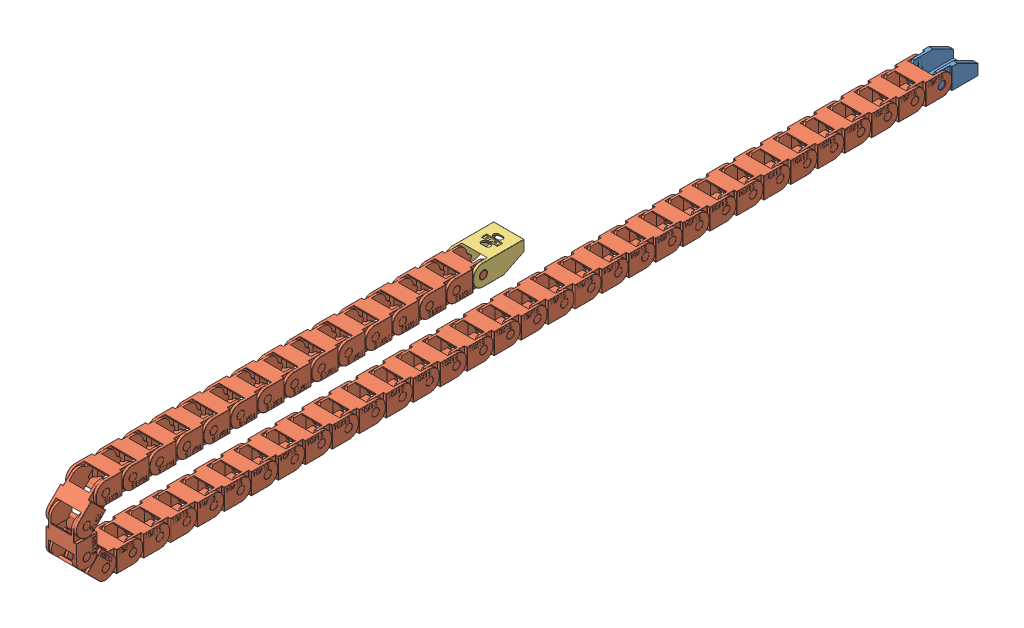
SolidWorks assembly Drag Chain Unit, configuration Default. Lengths in mm.
Overall size (23 71.62 674.15).
50 component instances, 3 part files, 147 mates.
Components (placement in the parent):
- Drag Chain 10x15 M-End-1: Drag Chain 10x15 M-End [Default] at origin size (21.7 15.5 37.5)
- Drag Chain 10x15 Inner-1: Drag Chain 10x15 Inner [Default] x (-1 0 0) z (0 0 1) size (23 15.5 37.5)
- Drag Chain 10x15 Inner-2: Drag Chain 10x15 Inner [Default] at (0 0 20) x (-1 0 0) z (0 0 1) size (23 15.5 37.5)
- Drag Chain 10x15 Inner-3: Drag Chain 10x15 Inner [Default] at (0 0 40) x (-1 0 0) z (0 0 1) size (23 15.5 37.5)
- Drag Chain 10x15 Inner-4: Drag Chain 10x15 Inner [Default] at (0 0 60) x (-1 0 0) z (0 0 1) size (23 15.5 37.5)
- Drag Chain 10x15 Inner-5: Drag Chain 10x15 Inner [Default] at (0 0 80) x (-1 0 0) z (0 0 1) size (23 15.5 37.5)
- Drag Chain 10x15 Inner-6: Drag Chain 10x15 Inner [Default] at (0 0 100) x (-1 0 0) z (0 0 1) size (23 15.5 37.5)
- Drag Chain 10x15 Inner-7: Drag Chain 10x15 Inner [Default] at (0 0 120) x (-1 0 0) z (0 0 1) size (23 15.5 37.5)
- Drag Chain 10x15 Inner-8: Drag Chain 10x15 Inner [Default] at (0 0 140) x (-1 0 0) z (0 0 1) size (23 15.5 37.5)
- Drag Chain 10x15 Inner-9: Drag Chain 10x15 Inner [Default] at (0 0 160) x (-1 0 0) z (0 0 1) size (23 15.5 37.5)
- Drag Chain 10x15 Inner-10: Drag Chain 10x15 Inner [Default] at (0 0 180) x (-1 0 0) z (0 0 1) size (23 15.5 37.5)
- Drag Chain 10x15 Inner-11: Drag Chain 10x15 Inner [Default] at (0 0 200) x (-1 0 0) z (0 0 1) size (23 15.5 37.5)
- Drag Chain 10x15 Inner-12: Drag Chain 10x15 Inner [Default] at (0 0 220) x (-1 0 0) z (0 0 1) size (23 15.5 37.5)
- Drag Chain 10x15 Inner-13: Drag Chain 10x15 Inner [Default] at (0 0 240) x (-1 0 0) z (0 0 1) size (23 15.5 37.5)
- Drag Chain 10x15 Inner-14: Drag Chain 10x15 Inner [Default] at (0 0 260) x (-1 0 0) z (0 0 1) size (23 15.5 37.5)
- Drag Chain 10x15 Inner-15: Drag Chain 10x15 Inner [Default] at (0 0 280) x (-1 0 0) z (0 0 1) size (23 15.5 37.5)
- Drag Chain 10x15 Inner-16: Drag Chain 10x15 Inner [Default] at (0 0 300) x (-1 0 0) z (0 0 1) size (23 15.5 37.5)
- Drag Chain 10x15 Inner-17: Drag Chain 10x15 Inner [Default] at (0 0 320) x (-1 0 0) z (0 0 1) size (23 15.5 37.5)
- Drag Chain 10x15 Inner-18: Drag Chain 10x15 Inner [Default] at (0 0 340) x (-1 0 0) z (0 0 1) size (23 15.5 37.5)
- Drag Chain 10x15 Inner-19: Drag Chain 10x15 Inner [Default] at (0 0 360) x (-1 0 0) z (0 0 1) size (23 15.5 37.5)
- Drag Chain 10x15 Inner-20: Drag Chain 10x15 Inner [Default] at (0 0 380) x (-1 0 0) z (0 0 1) size (23 15.5 37.5)
- Drag Chain 10x15 Inner-21: Drag Chain 10x15 Inner [Default] at (0 0 400) x (-1 0 0) z (0 0 1) size (23 15.5 37.5)
- Drag Chain 10x15 Inner-22: Drag Chain 10x15 Inner [Default] at (0 0 420) x (-1 0 0) z (0 0 1) size (23 15.5 37.5)
- Drag Chain 10x15 Inner-23: Drag Chain 10x15 Inner [Default] at (0 0 440) x (-1 0 0) z (0 0 1) size (23 15.5 37.5)
- Drag Chain 10x15 Inner-24: Drag Chain 10x15 Inner [Default] at (0 0 460) x (-1 0 0) z (0 0 1) size (23 15.5 37.5)
- Drag Chain 10x15 Inner-25: Drag Chain 10x15 Inner [Default] at (0 0 480) x (-1 0 0) z (0 0 1) size (23 15.5 37.5)
- Drag Chain 10x15 Inner-26: Drag Chain 10x15 Inner [Default] at (0 0 500) x (-1 0 0) z (0 0 1) size (23 15.5 37.5)
- Drag Chain 10x15 Inner-27: Drag Chain 10x15 Inner [Default] at (0 0 520) x (-1 0 0) z (0 0 1) size (23 15.5 37.5)
- Drag Chain 10x15 Inner-28: Drag Chain 10x15 Inner [Default] at (0 0 540) x (-1 0 0) z (0 0 1) size (23 15.5 37.5)
- Drag Chain 10x15 Inner-29: Drag Chain 10x15 Inner [Default] at (0 0 560) x (-1 0 0) z (0 0 1) size (23 15.5 37.5)
- Drag Chain 10x15 Inner-30: Drag Chain 10x15 Inner [Default] at (0 0 580) x (-1 0 0) z (0 0 1) size (23 15.5 37.5)
- Drag Chain 10x15 Inner-31: Drag Chain 10x15 Inner [Default] at (0 0 600) x (-1 0 0) z (0 0 1) size (23 15.5 37.5)
- Drag Chain 10x15 Inner-32: Drag Chain 10x15 Inner [Default] at (0 0 620) x (-1 0 0) z (0 0.707107 0.707107) size (23 15.5 37.5)
- Drag Chain 10x15 Inner-33: Drag Chain 10x15 Inner [Default] at (0 14.1421 634.1421) x (-1 0 0) z (0 1 0) size (23 15.5 37.5)
- Drag Chain 10x15 Inner-34: Drag Chain 10x15 Inner [Default] at (0 34.1421 634.1421) x (-1 0 0) z (0 0.707107 -0.707107) size (23 15.5 37.5)
- Drag Chain 10x15 Inner-35: Drag Chain 10x15 Inner [Default] at (0 48.2843 620) x (-1 0 0) z (0 0 -1) size (23 15.5 37.5)
- Drag Chain 10x15 Inner-36: Drag Chain 10x15 Inner [Default] at (0 48.2843 600) x (-1 0 0) z (0 0 -1) size (23 15.5 37.5)
- Drag Chain 10x15 Inner-37: Drag Chain 10x15 Inner [Default] at (0 48.2843 580) x (-1 0 0) z (0 0 -1) size (23 15.5 37.5)
- Drag Chain 10x15 Inner-38: Drag Chain 10x15 Inner [Default] at (0 48.2843 560) x (-1 0 0) z (0 0 -1) size (23 15.5 37.5)
- Drag Chain 10x15 Inner-39: Drag Chain 10x15 Inner [Default] at (0 48.2843 540) x (-1 0 0) z (0 0 -1) size (23 15.5 37.5)
- Drag Chain 10x15 Inner-40: Drag Chain 10x15 Inner [Default] at (0 48.2843 520) x (-1 0 0) z (0 0 -1) size (23 15.5 37.5)
- Drag Chain 10x15 Inner-41: Drag Chain 10x15 Inner [Default] at (0 48.2843 500) x (-1 0 0) z (0 0 -1) size (23 15.5 37.5)
- Drag Chain 10x15 Inner-42: Drag Chain 10x15 Inner [Default] at (0 48.2843 480) x (-1 0 0) z (0 0 -1) size (23 15.5 37.5)
- Drag Chain 10x15 Inner-43: Drag Chain 10x15 Inner [Default] at (0 48.2843 460) x (-1 0 0) z (0 0 -1) size (23 15.5 37.5)
- Drag Chain 10x15 Inner-44: Drag Chain 10x15 Inner [Default] at (0 48.2843 440) x (-1 0 0) z (0 0 -1) size (23 15.5 37.5)
- Drag Chain 10x15 Inner-45: Drag Chain 10x15 Inner [Default] at (0 48.2843 420) x (-1 0 0) z (0 0 -1) size (23 15.5 37.5)
- Drag Chain 10x15 Inner-46: Drag Chain 10x15 Inner [Default] at (0 48.2843 400) x (-1 0 0) z (0 0 -1) size (23 15.5 37.5)
- Drag Chain 10x15 Inner-47: Drag Chain 10x15 Inner [Default] at (0 48.2843 380) x (-1 0 0) z (0 0 -1) size (23 15.5 37.5)
- Drag Chain 10x15 Inner-48: Drag Chain 10x15 Inner [Default] at (0 48.2843 360) x (-1 0 0) z (0 0 -1) size (23 15.5 37.5)
- Drag Chain 10x15 F-End-1: Drag Chain 10x15 F-End [Default] at (0 48.2843 340) x (1 0 0) z (0 0 -1) size (22.5 15.5 37.5)
Mates (geometry in assembly coordinates):
- Coincident1: coincident: plane of assembly; plane of assembly; plane of Drag Chain 10x15 M-End-1 through (9.4 7.25 1.3258) normal (1 0 0); plane of Drag Chain 10x15 Inner-1 through (9.4 7.75 -7.35) normal (-1 0 0)
- Concentric1: concentric: cylinder of assembly; cylinder of assembly; cylinder of Drag Chain 10x15 M-End-1 through (9.4 0 0) axis (1 0 0) radius 2.8; cylinder of Drag Chain 10x15 Inner-1 through (-11.35 0 0) axis (1 0 0) radius 2.85
- Coincident2: coincident: plane of assembly; plane of assembly; plane of Drag Chain 10x15 M-End-1 through (10.85 -7.75 10.65) normal (0 -1 0); plane of Drag Chain 10x15 Inner-1 through (-11.35 -7.75 -7.35) normal (0 -1 0)
- Coincident3: coincident: plane of assembly; plane of assembly; plane of Drag Chain 10x15 Inner-1 through (9.4 -7.25 20.5989) normal (1 0 0); plane of Drag Chain 10x15 Inner-2 through (9.4 7.75 12.65) normal (-1 0 0)
- Concentric2: concentric: cylinder of assembly; cylinder of assembly; cylinder of Drag Chain 10x15 Inner-1 through (9.4 0 20) axis (1 0 0) radius 2.8; cylinder of Drag Chain 10x15 Inner-2 through (-11.35 0 20) axis (1 0 0) radius 2.85
- Coincident4: coincident: plane of assembly; plane of assembly; plane of Drag Chain 10x15 Inner-1 through (-11.35 -7.75 -7.35) normal (0 -1 0); plane of Drag Chain 10x15 Inner-2 through (-11.35 -7.75 12.65) normal (0 -1 0)
- Coincident5: coincident: plane of assembly; plane of assembly; plane of Drag Chain 10x15 Inner-2 through (9.4 -7.25 40.5989) normal (1 0 0); plane of Drag Chain 10x15 Inner-3 through (9.4 7.75 32.65) normal (-1 0 0)
- Concentric3: concentric: cylinder of assembly; cylinder of assembly; cylinder of Drag Chain 10x15 Inner-2 through (9.4 0 40) axis (1 0 0) radius 2.8; cylinder of Drag Chain 10x15 Inner-3 through (-11.35 0 40) axis (1 0 0) radius 2.85
- Coincident7: coincident: plane of assembly; plane of assembly; plane of Drag Chain 10x15 Inner-2 through (-11.35 -7.75 12.65) normal (0 -1 0); plane of Drag Chain 10x15 Inner-3 through (-11.35 -7.75 32.65) normal (0 -1 0)
- Coincident8: coincident: plane of assembly; plane of assembly; plane of Drag Chain 10x15 Inner-3 through (9.4 -7.25 60.5989) normal (1 0 0); plane of Drag Chain 10x15 Inner-4 through (9.4 7.75 52.65) normal (-1 0 0)
- Concentric4: concentric: cylinder of assembly; cylinder of assembly; cylinder of Drag Chain 10x15 Inner-3 through (9.4 0 60) axis (1 0 0) radius 2.8; cylinder of Drag Chain 10x15 Inner-4 through (-11.35 0 60) axis (1 0 0) radius 2.85
- Coincident9: coincident: plane of assembly; plane of assembly; plane of Drag Chain 10x15 Inner-3 through (-11.35 -7.75 32.65) normal (0 -1 0); plane of Drag Chain 10x15 Inner-4 through (-11.35 -7.75 52.65) normal (0 -1 0)
- Coincident10: coincident: plane of assembly; plane of assembly; plane of Drag Chain 10x15 Inner-4 through (9.4 -7.25 80.5989) normal (1 0 0); plane of Drag Chain 10x15 Inner-5 through (9.4 7.75 72.65) normal (-1 0 0)
- Concentric5: concentric: cylinder of assembly; cylinder of assembly; cylinder of Drag Chain 10x15 Inner-4 through (9.4 0 80) axis (1 0 0) radius 2.8; cylinder of Drag Chain 10x15 Inner-5 through (-11.35 0 80) axis (1 0 0) radius 2.85
- Coincident11: coincident: plane of assembly; plane of assembly; plane of Drag Chain 10x15 Inner-4 through (-11.35 -7.75 52.65) normal (0 -1 0); plane of Drag Chain 10x15 Inner-5 through (-11.35 -7.75 72.65) normal (0 -1 0)
- Coincident12: coincident: plane of assembly; plane of assembly; plane of Drag Chain 10x15 Inner-5 through (9.4 -7.25 100.5989) normal (1 0 0); plane of Drag Chain 10x15 Inner-6 through (9.4 7.75 92.65) normal (-1 0 0)
- Concentric6: concentric: cylinder of assembly; cylinder of assembly; cylinder of Drag Chain 10x15 Inner-5 through (9.4 0 100) axis (1 0 0) radius 2.8; cylinder of Drag Chain 10x15 Inner-6 through (-11.35 0 100) axis (1 0 0) radius 2.85
- Coincident13: coincident: plane of assembly; plane of assembly; plane of Drag Chain 10x15 Inner-5 through (-11.35 -7.75 72.65) normal (0 -1 0); plane of Drag Chain 10x15 Inner-6 through (-11.35 -7.75 92.65) normal (0 -1 0)
- Coincident14: coincident: plane of assembly; plane of assembly; plane of Drag Chain 10x15 Inner-6 through (9.4 -7.25 120.5989) normal (1 0 0); plane of Drag Chain 10x15 Inner-7 through (9.4 7.75 112.65) normal (-1 0 0)
- Concentric7: concentric: cylinder of assembly; cylinder of assembly; cylinder of Drag Chain 10x15 Inner-6 through (9.4 0 120) axis (1 0 0) radius 2.8; cylinder of Drag Chain 10x15 Inner-7 through (-11.35 0 120) axis (1 0 0) radius 2.85
- Coincident15: coincident: plane of assembly; plane of assembly; plane of Drag Chain 10x15 Inner-6 through (-11.35 -7.75 92.65) normal (0 -1 0); plane of Drag Chain 10x15 Inner-7 through (-11.35 -7.75 112.65) normal (0 -1 0)
- Coincident16: coincident: plane of assembly; plane of assembly; plane of Drag Chain 10x15 Inner-7 through (9.4 -7.25 140.5989) normal (1 0 0); plane of Drag Chain 10x15 Inner-8 through (9.4 7.75 132.65) normal (-1 0 0)
- Concentric8: concentric: cylinder of assembly; cylinder of assembly; cylinder of Drag Chain 10x15 Inner-7 through (9.4 0 140) axis (1 0 0) radius 2.8; cylinder of Drag Chain 10x15 Inner-8 through (-11.35 0 140) axis (1 0 0) radius 2.85
- Coincident17: coincident: plane of assembly; plane of assembly; plane of Drag Chain 10x15 Inner-7 through (-11.35 -7.75 112.65) normal (0 -1 0); plane of Drag Chain 10x15 Inner-8 through (-11.35 -7.75 132.65) normal (0 -1 0)
- Coincident18: coincident: plane of assembly; plane of assembly; plane of Drag Chain 10x15 Inner-8 through (9.4 -7.25 160.5989) normal (1 0 0); plane of Drag Chain 10x15 Inner-9 through (9.4 7.75 152.65) normal (-1 0 0)
- Concentric9: concentric: cylinder of assembly; cylinder of assembly; cylinder of Drag Chain 10x15 Inner-8 through (9.4 0 160) axis (1 0 0) radius 2.8; cylinder of Drag Chain 10x15 Inner-9 through (-11.35 0 160) axis (1 0 0) radius 2.85
- Coincident19: coincident: plane of assembly; plane of assembly; plane of Drag Chain 10x15 Inner-8 through (-11.35 -7.75 132.65) normal (0 -1 0); plane of Drag Chain 10x15 Inner-9 through (-11.35 -7.75 152.65) normal (0 -1 0)
- Coincident20: coincident: plane of assembly; plane of assembly; plane of Drag Chain 10x15 Inner-9 through (9.4 -7.25 180.5989) normal (1 0 0); plane of Drag Chain 10x15 Inner-10 through (9.4 7.75 172.65) normal (-1 0 0)
- Concentric10: concentric: cylinder of assembly; cylinder of assembly; cylinder of Drag Chain 10x15 Inner-9 through (9.4 0 180) axis (1 0 0) radius 2.8; cylinder of Drag Chain 10x15 Inner-10 through (-11.35 0 180) axis (1 0 0) radius 2.85
- Coincident21: coincident: plane of assembly; plane of assembly; plane of Drag Chain 10x15 Inner-9 through (-11.35 -7.75 152.65) normal (0 -1 0); plane of Drag Chain 10x15 Inner-10 through (-11.35 -7.75 172.65) normal (0 -1 0)
- Coincident22: coincident: plane of assembly; plane of assembly; plane of Drag Chain 10x15 Inner-10 through (9.4 -7.25 200.5989) normal (1 0 0); plane of Drag Chain 10x15 Inner-11 through (9.4 7.75 192.65) normal (-1 0 0)
- Concentric11: concentric: cylinder of assembly; cylinder of assembly; cylinder of Drag Chain 10x15 Inner-10 through (9.4 0 200) axis (1 0 0) radius 2.8; cylinder of Drag Chain 10x15 Inner-11 through (-11.35 0 200) axis (1 0 0) radius 2.85
- Coincident23: coincident: plane of assembly; plane of assembly; plane of Drag Chain 10x15 Inner-10 through (-11.35 -7.75 172.65) normal (0 -1 0); plane of Drag Chain 10x15 Inner-11 through (-11.35 -7.75 192.65) normal (0 -1 0)
- Coincident24: coincident: plane of assembly; plane of assembly; plane of Drag Chain 10x15 Inner-11 through (9.4 -7.25 220.5989) normal (1 0 0); plane of Drag Chain 10x15 Inner-12 through (9.4 7.75 212.65) normal (-1 0 0)
- Concentric12: concentric: cylinder of assembly; cylinder of assembly; cylinder of Drag Chain 10x15 Inner-11 through (9.4 0 220) axis (1 0 0) radius 2.8; cylinder of Drag Chain 10x15 Inner-12 through (-11.35 0 220) axis (1 0 0) radius 2.85
- Coincident25: coincident: plane of assembly; plane of assembly; plane of Drag Chain 10x15 Inner-11 through (-11.35 -7.75 192.65) normal (0 -1 0); plane of Drag Chain 10x15 Inner-12 through (-11.35 -7.75 212.65) normal (0 -1 0)
- Coincident26: coincident: plane of assembly; plane of assembly; plane of Drag Chain 10x15 Inner-12 through (9.4 -7.25 240.5989) normal (1 0 0); plane of Drag Chain 10x15 Inner-13 through (9.4 7.75 232.65) normal (-1 0 0)
- Concentric13: concentric: cylinder of assembly; cylinder of assembly; cylinder of Drag Chain 10x15 Inner-12 through (9.4 0 240) axis (1 0 0) radius 2.8; cylinder of Drag Chain 10x15 Inner-13 through (-11.35 0 240) axis (1 0 0) radius 2.85
- Coincident27: coincident: plane of assembly; plane of assembly; plane of Drag Chain 10x15 Inner-12 through (-11.35 -7.75 212.65) normal (0 -1 0); plane of Drag Chain 10x15 Inner-13 through (-11.35 -7.75 232.65) normal (0 -1 0)
- Coincident28: coincident: plane of assembly; plane of assembly; plane of Drag Chain 10x15 Inner-13 through (9.4 -7.25 260.5989) normal (1 0 0); plane of Drag Chain 10x15 Inner-14 through (9.4 7.75 252.65) normal (-1 0 0)
- Concentric14: concentric: cylinder of assembly; cylinder of assembly; cylinder of Drag Chain 10x15 Inner-13 through (9.4 0 260) axis (1 0 0) radius 2.8; cylinder of Drag Chain 10x15 Inner-14 through (-11.35 0 260) axis (1 0 0) radius 2.85
- Coincident29: coincident: plane of assembly; plane of assembly; plane of Drag Chain 10x15 Inner-13 through (-11.35 -7.75 232.65) normal (0 -1 0); plane of Drag Chain 10x15 Inner-14 through (-11.35 -7.75 252.65) normal (0 -1 0)
- Coincident30: coincident: plane of assembly; plane of assembly; plane of Drag Chain 10x15 Inner-14 through (9.4 -7.25 280.5989) normal (1 0 0); plane of Drag Chain 10x15 Inner-15 through (9.4 7.75 272.65) normal (-1 0 0)
- Concentric15: concentric: cylinder of assembly; cylinder of assembly; cylinder of Drag Chain 10x15 Inner-14 through (9.4 0 280) axis (1 0 0) radius 2.8; cylinder of Drag Chain 10x15 Inner-15 through (-11.35 0 280) axis (1 0 0) radius 2.85
- Coincident31: coincident: plane of assembly; plane of assembly; plane of Drag Chain 10x15 Inner-14 through (-11.35 -7.75 252.65) normal (0 -1 0); plane of Drag Chain 10x15 Inner-15 through (-11.35 -7.75 272.65) normal (0 -1 0)
- Coincident32: coincident: plane of assembly; plane of assembly; plane of Drag Chain 10x15 Inner-15 through (9.4 -7.25 300.5989) normal (1 0 0); plane of Drag Chain 10x15 Inner-16 through (9.4 7.75 292.65) normal (-1 0 0)
- Concentric16: concentric: cylinder of assembly; cylinder of assembly; cylinder of Drag Chain 10x15 Inner-15 through (9.4 0 300) axis (1 0 0) radius 2.8; cylinder of Drag Chain 10x15 Inner-16 through (-11.35 0 300) axis (1 0 0) radius 2.85
- Coincident33: coincident: plane of assembly; plane of assembly; plane of Drag Chain 10x15 Inner-15 through (-11.35 -7.75 272.65) normal (0 -1 0); plane of Drag Chain 10x15 Inner-16 through (-11.35 -7.75 292.65) normal (0 -1 0)
- Coincident34: coincident: plane of assembly; plane of assembly; plane of Drag Chain 10x15 Inner-16 through (9.4 -7.25 320.5989) normal (1 0 0); plane of Drag Chain 10x15 Inner-17 through (9.4 7.75 312.65) normal (-1 0 0)
- Concentric17: concentric: cylinder of assembly; cylinder of assembly; cylinder of Drag Chain 10x15 Inner-16 through (9.4 0 320) axis (1 0 0) radius 2.8; cylinder of Drag Chain 10x15 Inner-17 through (-11.35 0 320) axis (1 0 0) radius 2.85
- Coincident35: coincident: plane of assembly; plane of assembly; plane of Drag Chain 10x15 Inner-16 through (-11.35 -7.75 292.65) normal (0 -1 0); plane of Drag Chain 10x15 Inner-17 through (-11.35 -7.75 312.65) normal (0 -1 0)
- Coincident36: coincident: plane of assembly; plane of assembly; plane of Drag Chain 10x15 Inner-17 through (9.4 -7.25 340.5989) normal (1 0 0); plane of Drag Chain 10x15 Inner-18 through (9.4 7.75 332.65) normal (-1 0 0)
- Concentric18: concentric: cylinder of assembly; cylinder of assembly; cylinder of Drag Chain 10x15 Inner-17 through (9.4 0 340) axis (1 0 0) radius 2.8; cylinder of Drag Chain 10x15 Inner-18 through (-11.35 0 340) axis (1 0 0) radius 2.85
- Coincident37: coincident: plane of assembly; plane of assembly; plane of Drag Chain 10x15 Inner-17 through (-11.35 -7.75 312.65) normal (0 -1 0); plane of Drag Chain 10x15 Inner-18 through (-11.35 -7.75 332.65) normal (0 -1 0)
- Coincident38: coincident: plane of assembly; plane of assembly; plane of Drag Chain 10x15 Inner-18 through (9.4 -7.25 360.5989) normal (1 0 0); plane of Drag Chain 10x15 Inner-19 through (9.4 7.75 352.65) normal (-1 0 0)
- Concentric19: concentric: cylinder of assembly; cylinder of assembly; cylinder of Drag Chain 10x15 Inner-18 through (9.4 0 360) axis (1 0 0) radius 2.8; cylinder of Drag Chain 10x15 Inner-19 through (-11.35 0 360) axis (1 0 0) radius 2.85
- Coincident39: coincident: plane of assembly; plane of assembly; plane of Drag Chain 10x15 Inner-18 through (-11.35 -7.75 332.65) normal (0 -1 0); plane of Drag Chain 10x15 Inner-19 through (-11.35 -7.75 352.65) normal (0 -1 0)
- Coincident40: coincident: plane of assembly; plane of assembly; plane of Drag Chain 10x15 Inner-19 through (9.4 -7.25 380.5989) normal (1 0 0); plane of Drag Chain 10x15 Inner-20 through (9.4 7.75 372.65) normal (-1 0 0)
- Concentric20: concentric: cylinder of assembly; cylinder of assembly; cylinder of Drag Chain 10x15 Inner-19 through (9.4 0 380) axis (1 0 0) radius 2.8; cylinder of Drag Chain 10x15 Inner-20 through (-11.35 0 380) axis (1 0 0) radius 2.85
- Coincident41: coincident: plane of assembly; plane of assembly; plane of Drag Chain 10x15 Inner-19 through (-11.35 -7.75 352.65) normal (0 -1 0); plane of Drag Chain 10x15 Inner-20 through (-11.35 -7.75 372.65) normal (0 -1 0)
- Coincident42: coincident: plane of assembly; plane of assembly; plane of Drag Chain 10x15 Inner-20 through (9.4 -7.25 400.5989) normal (1 0 0); plane of Drag Chain 10x15 Inner-21 through (9.4 7.75 392.65) normal (-1 0 0)
- Concentric21: concentric: cylinder of assembly; cylinder of assembly; cylinder of Drag Chain 10x15 Inner-20 through (9.4 0 400) axis (1 0 0) radius 2.8; cylinder of Drag Chain 10x15 Inner-21 through (-11.35 0 400) axis (1 0 0) radius 2.85
- Coincident44: coincident: plane of assembly; plane of assembly; plane of Drag Chain 10x15 Inner-20 through (-11.35 -7.75 372.65) normal (0 -1 0); plane of Drag Chain 10x15 Inner-21 through (-11.35 -7.75 392.65) normal (0 -1 0)
- Coincident45: coincident: plane of assembly; plane of assembly; plane of Drag Chain 10x15 Inner-21 through (9.4 -7.25 420.5989) normal (1 0 0); plane of Drag Chain 10x15 Inner-22 through (9.4 7.75 412.65) normal (-1 0 0)
- Concentric22: concentric: cylinder of assembly; cylinder of assembly; cylinder of Drag Chain 10x15 Inner-21 through (9.4 0 420) axis (1 0 0) radius 2.8; cylinder of Drag Chain 10x15 Inner-22 through (-11.35 0 420) axis (1 0 0) radius 2.85
- Coincident46: coincident: plane of assembly; plane of assembly; plane of Drag Chain 10x15 Inner-21 through (-11.35 -7.75 392.65) normal (0 -1 0); plane of Drag Chain 10x15 Inner-22 through (-11.35 -7.75 412.65) normal (0 -1 0)
- Coincident47: coincident: plane of assembly; plane of assembly; plane of Drag Chain 10x15 Inner-22 through (9.4 -7.25 440.5989) normal (1 0 0); plane of Drag Chain 10x15 Inner-23 through (9.4 7.75 432.65) normal (-1 0 0)
- Concentric23: concentric: cylinder of assembly; cylinder of assembly; cylinder of Drag Chain 10x15 Inner-22 through (9.4 0 440) axis (1 0 0) radius 2.8; cylinder of Drag Chain 10x15 Inner-23 through (-11.35 0 440) axis (1 0 0) radius 2.85
- Coincident48: coincident: plane of assembly; plane of assembly; plane of Drag Chain 10x15 Inner-22 through (-11.35 -7.75 412.65) normal (0 -1 0); plane of Drag Chain 10x15 Inner-23 through (-11.35 -7.75 432.65) normal (0 -1 0)
- Coincident49: coincident: plane of assembly; plane of assembly; plane of Drag Chain 10x15 Inner-23 through (9.4 -7.25 460.5989) normal (1 0 0); plane of Drag Chain 10x15 Inner-24 through (9.4 7.75 452.65) normal (-1 0 0)
- Concentric24: concentric: cylinder of assembly; cylinder of assembly; cylinder of Drag Chain 10x15 Inner-23 through (9.4 0 460) axis (1 0 0) radius 2.8; cylinder of Drag Chain 10x15 Inner-24 through (-11.35 0 460) axis (1 0 0) radius 2.85
- Coincident50: coincident: plane of assembly; plane of assembly; plane of Drag Chain 10x15 Inner-23 through (-11.35 -7.75 432.65) normal (0 -1 0); plane of Drag Chain 10x15 Inner-24 through (-11.35 -7.75 452.65) normal (0 -1 0)
- Coincident51: coincident: plane of assembly; plane of assembly; plane of Drag Chain 10x15 Inner-24 through (9.4 -7.25 480.5989) normal (1 0 0); plane of Drag Chain 10x15 Inner-25 through (9.4 7.75 472.65) normal (-1 0 0)
- Concentric25: concentric: cylinder of assembly; cylinder of assembly; cylinder of Drag Chain 10x15 Inner-24 through (9.4 0 480) axis (1 0 0) radius 2.8; cylinder of Drag Chain 10x15 Inner-25 through (-11.35 0 480) axis (1 0 0) radius 2.85
- Coincident52: coincident: plane of assembly; plane of assembly; plane of Drag Chain 10x15 Inner-24 through (-11.35 -7.75 452.65) normal (0 -1 0); plane of Drag Chain 10x15 Inner-25 through (-11.35 -7.75 472.65) normal (0 -1 0)
- Coincident53: coincident: plane of assembly; plane of assembly; plane of Drag Chain 10x15 Inner-25 through (9.4 -7.25 500.5989) normal (1 0 0); plane of Drag Chain 10x15 Inner-26 through (9.4 7.75 492.65) normal (-1 0 0)
- Concentric26: concentric: cylinder of assembly; cylinder of assembly; cylinder of Drag Chain 10x15 Inner-25 through (9.4 0 500) axis (1 0 0) radius 2.8; cylinder of Drag Chain 10x15 Inner-26 through (-11.35 0 500) axis (1 0 0) radius 2.85
- Coincident54: coincident: plane of assembly; plane of assembly; plane of Drag Chain 10x15 Inner-25 through (-11.35 -7.75 472.65) normal (0 -1 0); plane of Drag Chain 10x15 Inner-26 through (-11.35 -7.75 492.65) normal (0 -1 0)
- Coincident55: coincident: plane of assembly; plane of assembly; plane of Drag Chain 10x15 Inner-26 through (9.4 -7.25 520.5989) normal (1 0 0); plane of Drag Chain 10x15 Inner-27 through (9.4 7.75 512.65) normal (-1 0 0)
- Concentric28: concentric: cylinder of assembly; cylinder of assembly; cylinder of Drag Chain 10x15 Inner-26 through (9.4 0 520) axis (1 0 0) radius 2.8; cylinder of Drag Chain 10x15 Inner-27 through (-11.35 0 520) axis (1 0 0) radius 2.85
- Coincident56: coincident: plane of assembly; plane of assembly; plane of Drag Chain 10x15 Inner-26 through (-11.35 -7.75 492.65) normal (0 -1 0); plane of Drag Chain 10x15 Inner-27 through (-11.35 -7.75 512.65) normal (0 -1 0)
- Coincident57: coincident: plane of assembly; plane of assembly; plane of Drag Chain 10x15 Inner-27 through (9.4 -7.25 540.5989) normal (1 0 0); plane of Drag Chain 10x15 Inner-28 through (9.4 7.75 532.65) normal (-1 0 0)
- Concentric29: concentric: cylinder of assembly; cylinder of assembly; cylinder of Drag Chain 10x15 Inner-27 through (9.4 0 540) axis (1 0 0) radius 2.8; cylinder of Drag Chain 10x15 Inner-28 through (-11.35 0 540) axis (1 0 0) radius 2.85
- Coincident58: coincident: plane of assembly; plane of assembly; plane of Drag Chain 10x15 Inner-27 through (-11.35 -7.75 512.65) normal (0 -1 0); plane of Drag Chain 10x15 Inner-28 through (-11.35 -7.75 532.65) normal (0 -1 0)
- Coincident59: coincident: plane of assembly; plane of assembly; plane of Drag Chain 10x15 Inner-28 through (9.4 -7.25 560.5989) normal (1 0 0); plane of Drag Chain 10x15 Inner-29 through (9.4 7.75 552.65) normal (-1 0 0)
- Concentric30: concentric: cylinder of assembly; cylinder of assembly; cylinder of Drag Chain 10x15 Inner-28 through (9.4 0 560) axis (1 0 0) radius 2.8; cylinder of Drag Chain 10x15 Inner-29 through (-11.35 0 560) axis (1 0 0) radius 2.85
- Coincident60: coincident: plane of assembly; plane of assembly; plane of Drag Chain 10x15 Inner-28 through (-11.35 -7.75 532.65) normal (0 -1 0); plane of Drag Chain 10x15 Inner-29 through (-11.35 -7.75 552.65) normal (0 -1 0)
- Concentric31: concentric: cylinder of assembly; cylinder of assembly; cylinder of Drag Chain 10x15 Inner-29 through (9.4 0 580) axis (1 0 0) radius 2.8; cylinder of Drag Chain 10x15 Inner-30 through (-11.35 0 580) axis (1 0 0) radius 2.85
- Coincident61: coincident: plane of assembly; plane of assembly; plane of Drag Chain 10x15 Inner-29 through (9.4 -7.25 580.5989) normal (1 0 0); plane of Drag Chain 10x15 Inner-30 through (9.4 7.75 572.65) normal (-1 0 0)
- Coincident63: coincident: plane of assembly; plane of assembly; plane of Drag Chain 10x15 Inner-29 through (-11.35 -7.75 552.65) normal (0 -1 0); plane of Drag Chain 10x15 Inner-30 through (-11.35 -7.75 572.65) normal (0 -1 0)
- Coincident64: coincident: plane of assembly; plane of assembly; plane of Drag Chain 10x15 Inner-30 through (9.4 -7.25 600.5989) normal (1 0 0); plane of Drag Chain 10x15 Inner-31 through (9.4 7.75 592.65) normal (-1 0 0)
- Concentric32: concentric: cylinder of assembly; cylinder of assembly; cylinder of Drag Chain 10x15 Inner-30 through (9.4 0 600) axis (1 0 0) radius 2.8; cylinder of Drag Chain 10x15 Inner-31 through (-11.35 0 600) axis (1 0 0) radius 2.85
- Coincident65: coincident: plane of assembly; plane of assembly; plane of Drag Chain 10x15 Inner-30 through (-11.35 -7.75 572.65) normal (0 -1 0); plane of Drag Chain 10x15 Inner-31 through (-11.35 -7.75 592.65) normal (0 -1 0)
- Coincident66: coincident: plane of assembly; plane of assembly; plane of Drag Chain 10x15 Inner-31 through (9.4 -7.25 620.5989) normal (1 0 0); plane of Drag Chain 10x15 Inner-32 through (9.4 0.2828 609.3227) normal (-1 0 0)
- Concentric33: concentric: cylinder of assembly; cylinder of assembly; cylinder of Drag Chain 10x15 Inner-31 through (9.4 0 620) axis (1 0 0) radius 2.8; cylinder of Drag Chain 10x15 Inner-32 through (-11.35 0 620) axis (1 0 0) radius 2.85
- LimitAngle1: limit planar angle = 0.785398 rad: plane of assembly; plane of assembly; plane of Drag Chain 10x15 Inner-31 through (-11.35 -7.75 592.65) normal (0 -1 0); plane of Drag Chain 10x15 Inner-32 through (-11.35 -10.6773 620.2828) normal (0 -0.707107 0.707107)
- Coincident68: coincident: plane of assembly; plane of assembly; plane of Drag Chain 10x15 Inner-32 through (9.4 9.4391 639.6921) normal (1 0 0); plane of Drag Chain 10x15 Inner-33 through (9.4 6.7921 626.3921) normal (-1 0 0)
- Concentric34: concentric: cylinder of assembly; cylinder of assembly; cylinder of Drag Chain 10x15 Inner-32 through (9.4 14.1421 634.1421) axis (1 0 0) radius 2.8; cylinder of Drag Chain 10x15 Inner-33 through (-11.35 14.1421 634.1421) axis (1 0 0) radius 2.85
- LimitAngle3: limit planar angle = 0.785398 rad: plane of assembly; plane of assembly; plane of Drag Chain 10x15 Inner-32 through (-11.35 -10.6773 620.2828) normal (0 -0.707107 0.707107); plane of Drag Chain 10x15 Inner-33 through (-11.35 6.7921 641.8921) normal (0 0 1)
- Coincident70: coincident: plane of assembly; plane of assembly; plane of Drag Chain 10x15 Inner-33 through (9.4 34.741 641.3921) normal (1 0 0); plane of Drag Chain 10x15 Inner-34 through (9.4 23.4648 633.8593) normal (-1 0 0)
- Concentric35: concentric: cylinder of assembly; cylinder of assembly; cylinder of Drag Chain 10x15 Inner-33 through (9.4 34.1421 634.1421) axis (1 0 0) radius 2.8; cylinder of Drag Chain 10x15 Inner-34 through (-11.35 34.1421 634.1421) axis (1 0 0) radius 2.85
- LimitAngle4: limit planar angle = 0.785398 rad: plane of assembly; plane of assembly; plane of Drag Chain 10x15 Inner-33 through (-11.35 6.7921 641.8921) normal (0 0 1); plane of Drag Chain 10x15 Inner-34 through (-11.35 34.425 644.8194) normal (0 0.707107 0.707107)
- Coincident72: coincident: plane of assembly; plane of assembly; plane of Drag Chain 10x15 Inner-34 through (9.4 53.8343 624.703) normal (1 0 0); plane of Drag Chain 10x15 Inner-35 through (9.4 40.5343 627.35) normal (-1 0 0)
- Concentric36: concentric: cylinder of assembly; cylinder of assembly; cylinder of Drag Chain 10x15 Inner-34 through (9.4 48.2843 620) axis (1 0 0) radius 2.8; cylinder of Drag Chain 10x15 Inner-35 through (-11.35 48.2843 620) axis (1 0 0) radius 2.85
- LimitAngle5: limit planar angle = 0.785398 rad: plane of assembly; plane of assembly; plane of Drag Chain 10x15 Inner-34 through (-11.35 34.425 644.8194) normal (0 0.707107 0.707107); plane of Drag Chain 10x15 Inner-35 through (-11.35 56.0343 627.35) normal (0 1 0)
- Coincident74: coincident: plane of assembly; plane of assembly; plane of Drag Chain 10x15 Inner-35 through (9.4 55.5343 599.4011) normal (1 0 0); plane of Drag Chain 10x15 Inner-36 through (9.4 40.5343 607.35) normal (-1 0 0)
- Concentric37: concentric: cylinder of assembly; cylinder of assembly; cylinder of Drag Chain 10x15 Inner-35 through (9.4 48.2843 600) axis (1 0 0) radius 2.8; cylinder of Drag Chain 10x15 Inner-36 through (-11.35 48.2843 600) axis (1 0 0) radius 2.85
- Coincident75: coincident: plane of assembly; plane of assembly; plane of Drag Chain 10x15 Inner-35 through (-11.35 56.0343 627.35) normal (0 1 0); plane of Drag Chain 10x15 Inner-36 through (-11.35 56.0343 607.35) normal (0 1 0)
- Coincident76: coincident: plane of assembly; plane of assembly; plane of Drag Chain 10x15 Inner-36 through (9.4 55.5343 579.4011) normal (1 0 0); plane of Drag Chain 10x15 Inner-37 through (9.4 40.5343 587.35) normal (-1 0 0)
- Concentric38: concentric: cylinder of assembly; cylinder of assembly; cylinder of Drag Chain 10x15 Inner-36 through (9.4 48.2843 580) axis (1 0 0) radius 2.8; cylinder of Drag Chain 10x15 Inner-37 through (-11.35 48.2843 580) axis (1 0 0) radius 2.85
- Coincident77: coincident: plane of assembly; plane of assembly; plane of Drag Chain 10x15 Inner-36 through (-11.35 56.0343 607.35) normal (0 1 0); plane of Drag Chain 10x15 Inner-37 through (-11.35 56.0343 587.35) normal (0 1 0)
- Coincident78: coincident: plane of assembly; plane of assembly; plane of Drag Chain 10x15 Inner-37 through (9.4 55.5343 559.4011) normal (1 0 0); plane of Drag Chain 10x15 Inner-38 through (9.4 40.5343 567.35) normal (-1 0 0)
- Concentric39: concentric: cylinder of assembly; cylinder of assembly; cylinder of Drag Chain 10x15 Inner-37 through (9.4 48.2843 560) axis (1 0 0) radius 2.8; cylinder of Drag Chain 10x15 Inner-38 through (-11.35 48.2843 560) axis (1 0 0) radius 2.85
- Coincident79: coincident: plane of assembly; plane of assembly; plane of Drag Chain 10x15 Inner-37 through (-11.35 56.0343 587.35) normal (0 1 0); plane of Drag Chain 10x15 Inner-38 through (-11.35 56.0343 567.35) normal (0 1 0)
- Coincident80: coincident: plane of assembly; plane of assembly; plane of Drag Chain 10x15 Inner-38 through (9.4 55.5343 539.4011) normal (1 0 0); plane of Drag Chain 10x15 Inner-39 through (9.4 40.5343 547.35) normal (-1 0 0)
- Concentric40: concentric: cylinder of assembly; cylinder of assembly; cylinder of Drag Chain 10x15 Inner-38 through (9.4 48.2843 540) axis (1 0 0) radius 2.8; cylinder of Drag Chain 10x15 Inner-39 through (-11.35 48.2843 540) axis (1 0 0) radius 2.85
- Coincident81: coincident: plane of assembly; plane of assembly; plane of Drag Chain 10x15 Inner-38 through (-11.35 56.0343 567.35) normal (0 1 0); plane of Drag Chain 10x15 Inner-39 through (-11.35 56.0343 547.35) normal (0 1 0)
- Coincident82: coincident: plane of assembly; plane of assembly; plane of Drag Chain 10x15 Inner-39 through (9.4 55.5343 519.4011) normal (1 0 0); plane of Drag Chain 10x15 Inner-40 through (9.4 40.5343 527.35) normal (-1 0 0)
- Concentric41: concentric: cylinder of assembly; cylinder of assembly; cylinder of Drag Chain 10x15 Inner-39 through (9.4 48.2843 520) axis (1 0 0) radius 2.8; cylinder of Drag Chain 10x15 Inner-40 through (-11.35 48.2843 520) axis (1 0 0) radius 2.85
- Coincident83: coincident: plane of assembly; plane of assembly; plane of Drag Chain 10x15 Inner-39 through (-11.35 56.0343 547.35) normal (0 1 0); plane of Drag Chain 10x15 Inner-40 through (-11.35 56.0343 527.35) normal (0 1 0)
- Coincident84: coincident: plane of assembly; plane of assembly; plane of Drag Chain 10x15 Inner-40 through (9.4 55.5343 499.4011) normal (1 0 0); plane of Drag Chain 10x15 Inner-41 through (9.4 40.5343 507.35) normal (-1 0 0)
- Concentric42: concentric: cylinder of assembly; cylinder of assembly; cylinder of Drag Chain 10x15 Inner-40 through (9.4 48.2843 500) axis (1 0 0) radius 2.8; cylinder of Drag Chain 10x15 Inner-41 through (-11.35 48.2843 500) axis (1 0 0) radius 2.85
- Coincident85: coincident: plane of assembly; plane of assembly; plane of Drag Chain 10x15 Inner-40 through (-11.35 56.0343 527.35) normal (0 1 0); plane of Drag Chain 10x15 Inner-41 through (-11.35 56.0343 507.35) normal (0 1 0)
- Coincident86: coincident: plane of assembly; plane of assembly; plane of Drag Chain 10x15 Inner-41 through (9.4 55.5343 479.4011) normal (1 0 0); plane of Drag Chain 10x15 Inner-42 through (9.4 40.5343 487.35) normal (-1 0 0)
- Concentric43: concentric: cylinder of assembly; cylinder of assembly; cylinder of Drag Chain 10x15 Inner-41 through (9.4 48.2843 480) axis (1 0 0) radius 2.8; cylinder of Drag Chain 10x15 Inner-42 through (-11.35 48.2843 480) axis (1 0 0) radius 2.85
- Coincident87: coincident: plane of assembly; plane of assembly; plane of Drag Chain 10x15 Inner-41 through (-11.35 56.0343 507.35) normal (0 1 0); plane of Drag Chain 10x15 Inner-42 through (-11.35 56.0343 487.35) normal (0 1 0)
- Coincident88: coincident: plane of assembly; plane of assembly; plane of Drag Chain 10x15 Inner-42 through (9.4 55.5343 459.4011) normal (1 0 0); plane of Drag Chain 10x15 Inner-43 through (9.4 40.5343 467.35) normal (-1 0 0)
- Concentric44: concentric: cylinder of assembly; cylinder of assembly; cylinder of Drag Chain 10x15 Inner-42 through (9.4 48.2843 460) axis (1 0 0) radius 2.8; cylinder of Drag Chain 10x15 Inner-43 through (-11.35 48.2843 460) axis (1 0 0) radius 2.85
- Coincident89: coincident: plane of assembly; plane of assembly; plane of Drag Chain 10x15 Inner-42 through (-11.35 56.0343 487.35) normal (0 1 0); plane of Drag Chain 10x15 Inner-43 through (-11.35 56.0343 467.35) normal (0 1 0)
- Coincident90: coincident: plane of assembly; plane of assembly; plane of Drag Chain 10x15 Inner-43 through (9.4 55.5343 439.4011) normal (1 0 0); plane of Drag Chain 10x15 Inner-44 through (9.4 40.5343 447.35) normal (-1 0 0)
- Concentric45: concentric: cylinder of assembly; cylinder of assembly; cylinder of Drag Chain 10x15 Inner-43 through (9.4 48.2843 440) axis (1 0 0) radius 2.8; cylinder of Drag Chain 10x15 Inner-44 through (-11.35 48.2843 440) axis (1 0 0) radius 2.85
- Coincident91: coincident: plane of assembly; plane of assembly; plane of Drag Chain 10x15 Inner-43 through (-11.35 56.0343 467.35) normal (0 1 0); plane of Drag Chain 10x15 Inner-44 through (-11.35 56.0343 447.35) normal (0 1 0)
- Coincident92: coincident: plane of assembly; plane of assembly; plane of Drag Chain 10x15 Inner-44 through (9.4 55.5343 419.4011) normal (1 0 0); plane of Drag Chain 10x15 Inner-45 through (9.4 40.5343 427.35) normal (-1 0 0)
- Concentric46: concentric: cylinder of assembly; cylinder of assembly; cylinder of Drag Chain 10x15 Inner-44 through (9.4 48.2843 420) axis (1 0 0) radius 2.8; cylinder of Drag Chain 10x15 Inner-45 through (-11.35 48.2843 420) axis (1 0 0) radius 2.85
- Coincident93: coincident: plane of assembly; plane of assembly; plane of Drag Chain 10x15 Inner-44 through (-11.35 56.0343 447.35) normal (0 1 0); plane of Drag Chain 10x15 Inner-45 through (-11.35 56.0343 427.35) normal (0 1 0)
- Coincident94: coincident: plane of assembly; plane of assembly; plane of Drag Chain 10x15 Inner-45 through (9.4 55.5343 399.4011) normal (1 0 0); plane of Drag Chain 10x15 Inner-46 through (9.4 40.5343 407.35) normal (-1 0 0)
- Concentric47: concentric: cylinder of assembly; cylinder of assembly; cylinder of Drag Chain 10x15 Inner-45 through (9.4 48.2843 400) axis (1 0 0) radius 2.8; cylinder of Drag Chain 10x15 Inner-46 through (-11.35 48.2843 400) axis (1 0 0) radius 2.85
- Coincident95: coincident: plane of assembly; plane of assembly; plane of Drag Chain 10x15 Inner-45 through (-11.35 56.0343 427.35) normal (0 1 0); plane of Drag Chain 10x15 Inner-46 through (-11.35 56.0343 407.35) normal (0 1 0)
- Coincident96: coincident: plane of assembly; plane of assembly; plane of Drag Chain 10x15 Inner-46 through (9.4 55.5343 379.4011) normal (1 0 0); plane of Drag Chain 10x15 Inner-47 through (9.4 40.5343 387.35) normal (-1 0 0)
- Concentric48: concentric: cylinder of assembly; cylinder of assembly; cylinder of Drag Chain 10x15 Inner-46 through (9.4 48.2843 380) axis (1 0 0) radius 2.8; cylinder of Drag Chain 10x15 Inner-47 through (-11.35 48.2843 380) axis (1 0 0) radius 2.85
- Coincident97: coincident: plane of assembly; plane of assembly; plane of Drag Chain 10x15 Inner-46 through (-11.35 56.0343 407.35) normal (0 1 0); plane of Drag Chain 10x15 Inner-47 through (-11.35 56.0343 387.35) normal (0 1 0)
- Coincident98: coincident: plane of assembly; plane of assembly; plane of Drag Chain 10x15 Inner-47 through (9.4 55.5343 359.4011) normal (1 0 0); plane of Drag Chain 10x15 Inner-48 through (9.4 40.5343 367.35) normal (-1 0 0)
- Concentric49: concentric: cylinder of assembly; cylinder of assembly; cylinder of Drag Chain 10x15 Inner-47 through (9.4 48.2843 360) axis (1 0 0) radius 2.8; cylinder of Drag Chain 10x15 Inner-48 through (-11.35 48.2843 360) axis (1 0 0) radius 2.85
- Coincident99: coincident: plane of assembly; plane of assembly; plane of Drag Chain 10x15 Inner-47 through (-11.35 56.0343 387.35) normal (0 1 0); plane of Drag Chain 10x15 Inner-48 through (-11.35 56.0343 367.35) normal (0 1 0)
- Concentric50: concentric: cylinder of assembly; cylinder of assembly; cylinder of Drag Chain 10x15 Inner-48 through (9.4 48.2843 340) axis (1 0 0) radius 2.8; cylinder of Drag Chain 10x15 F-End-1 through (11.25 48.2843 340) axis (-1 0 0) radius 2.85
- Coincident100: coincident: plane of assembly; plane of assembly; plane of Drag Chain 10x15 Inner-48 through (9.4 55.5343 339.4011) normal (1 0 0); plane of Drag Chain 10x15 F-End-1 through (9.4 40.5343 347.35) normal (-1 0 0)
- Coincident102: coincident: plane of assembly; plane of assembly; plane of Drag Chain 10x15 Inner-48 through (-11.35 56.0343 367.35) normal (0 1 0); plane of Drag Chain 10x15 F-End-1 through (11.25 56.0343 347.35) normal (0 1 0)
